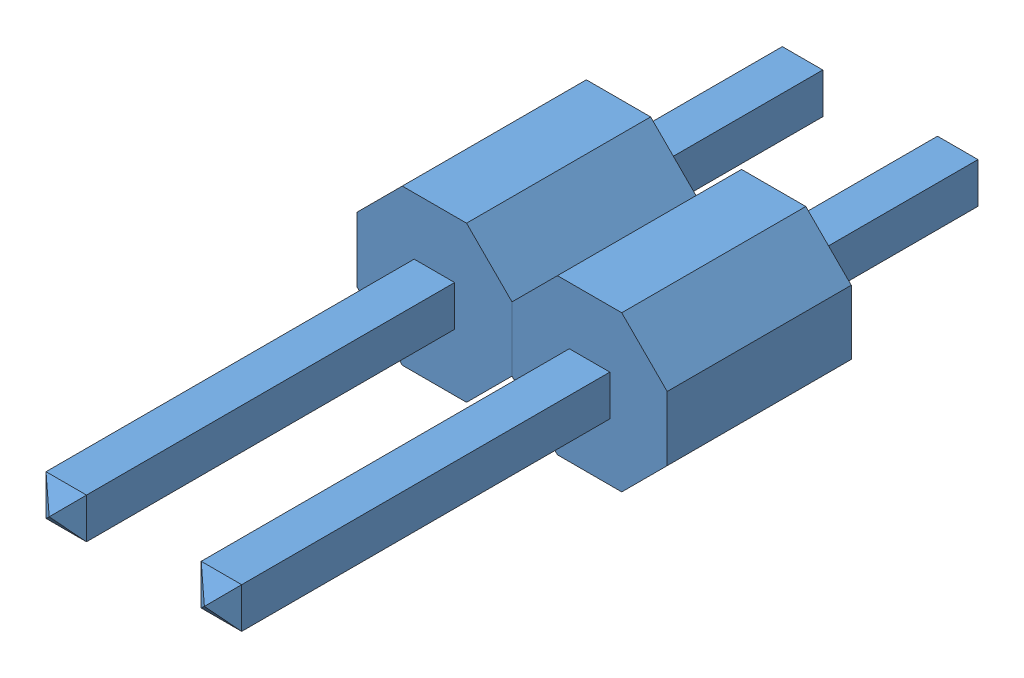
SolidWorks assembly Componente_1, configuration Default. Lengths in mm.
Overall size (5.25 2.82 12.38).
2 component instances, 1 part files, 0 mates.
Components (placement in the parent):
- Pin-1: Pin [Default] at (1.2601 0 0) x (0 1 0) z (0 0 1) size (2.82 2.73 12.38)
- Pin-2: Pin [Default] at (-1.2601 0 0) x (0 1 0) z (0 0 1) size (2.82 2.73 12.38)
